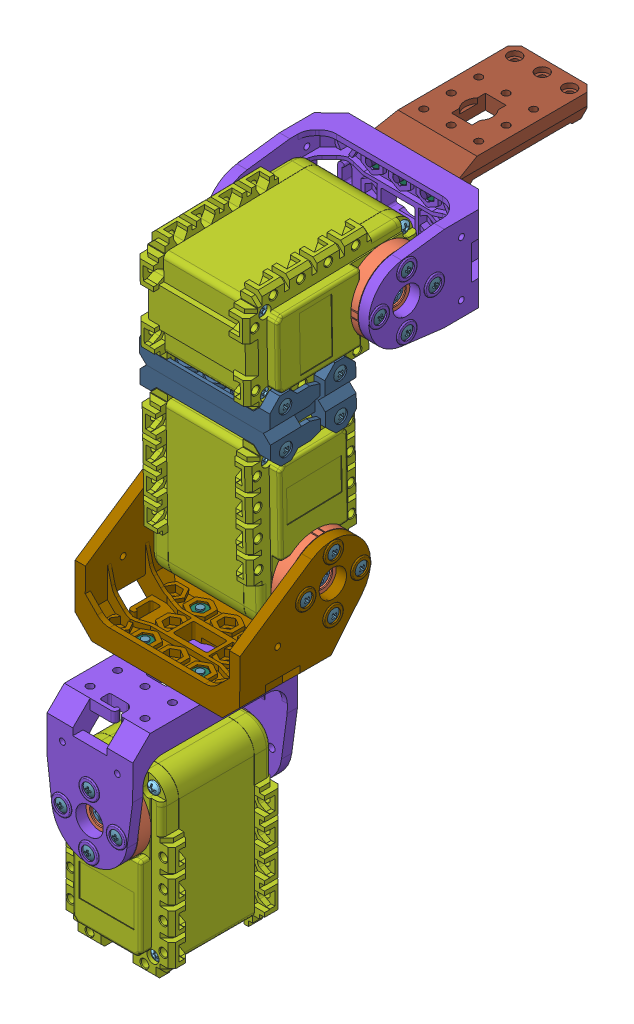
SolidWorks assembly Pate, configuration Défaut. Lengths in mm.
Overall size (51 164.97 135.04).
101 component instances, 17 part files, 139 mates.
Components (placement in the parent):
- AX-12A-1: AX-12A [Défaut] at (-17.6029 32.8619 -0.956) size (32 50.04 40.25)
  - BHS_M2_6X8-1: BHS_M2_6X8 [Défaut] at (0 0 19.48) x (-1 0 0) z (0 1 0) size (5.5 9.6 5.5)
  - DC04_B01_HORN2_DUMMY-1: DC04_B01_HORN2_DUMMY [Défaut] at (0 0 19.03) x (0 1 0) z (0 0 1) size (22 22 6.7)
  - DC04_B01_INSERT_M3-1: DC04_B01_INSERT_M3 [Défaut] at (0 0 -18.4) x (-1 0 0) z (0 1 0) size (4.98 7 4.98)
  - 099990987____-1: 099990987____ [Défaut] at (5.05 -15.19 -9.75) x (1 0 0) z (0 1 0) size (9.9 9.43 4.9)
  - 099990987____-2: 099990987____ [Défaut] at (-4.95 -15.19 -9.75) x (1 0 0) z (0 1 0) size (9.9 9.43 4.9)
  - DX124_SCREW-COVER___-1: DX124_SCREW-COVER___ [Défaut] at (9.5 8.5 14.5) x (-1 0 0) z (0 1 0) size (3.5 30.7 3.5)
  - DX124_SCREW-COVER___-2: DX124_SCREW-COVER___ [Défaut] at (-9.5 8.5 14.5) x (-1 0 0) z (0 1 0) size (3.5 30.7 3.5)
  - DX124_SCREW-COVER___-3: DX124_SCREW-COVER___ [Défaut] at (10.5 -33 14.5) x (-1 0 0) z (0 1 0) size (3.5 30.7 3.5)
  - DX124_SCREW-COVER___-4: DX124_SCREW-COVER___ [Défaut] at (-10.5 -33 14.5) x (-1 0 0) z (0 1 0) size (3.5 30.7 3.5)
  - ASSY_GEAR-WHEEL___DUMMY-1: ASSY_GEAR-WHEEL___DUMMY [Défaut] at (0 0 -2) x (-1 0 0) z (0 0 1) size (6.5 6.5 5.51)
  - ASSY_DUMMY___-1: ASSY_DUMMY___ [Défaut] at origin size (32 50.04 38.37)
- F2-1: F2 [Défaut] at (-17.6029 32.8619 -0.956) x (0 0 -1) z (0.007281 0.999973 0) size (48.81 25 37)
- F1-1: F1 [Défaut] at (-17.2461 81.8606 -23.456) x (0.999973 -0.007281 0) z (-0.007281 -0.999973 0) size (48.81 38 34)
- AX-12A-2: AX-12A [Défaut] at (-17.2461 81.8606 -23.456) x (-0.000183 -0.025088 0.999685) z (0.999973 -0.007281 0) size (32 50.04 40.25)
  - BHS_M2_6X8-1: BHS_M2_6X8 [Défaut] at (0 0 19.48) x (-1 0 0) z (0 1 0) size (5.5 9.6 5.5)
  - DC04_B01_HORN2_DUMMY-1: DC04_B01_HORN2_DUMMY [Défaut] at (0 0 19.03) x (0 1 0) z (0 0 1) size (22 22 6.7)
  - DC04_B01_INSERT_M3-1: DC04_B01_INSERT_M3 [Défaut] at (0 0 -18.4) x (-1 0 0) z (0 1 0) size (4.98 7 4.98)
  - 099990987____-1: 099990987____ [Défaut] at (5.05 -15.19 -9.75) x (1 0 0) z (0 1 0) size (9.9 9.43 4.9)
  - 099990987____-2: 099990987____ [Défaut] at (-4.95 -15.19 -9.75) x (1 0 0) z (0 1 0) size (9.9 9.43 4.9)
  - DX124_SCREW-COVER___-1: DX124_SCREW-COVER___ [Défaut] at (9.5 8.5 14.5) x (-1 0 0) z (0 1 0) size (3.5 30.7 3.5)
  - DX124_SCREW-COVER___-2: DX124_SCREW-COVER___ [Défaut] at (-9.5 8.5 14.5) x (-1 0 0) z (0 1 0) size (3.5 30.7 3.5)
  - DX124_SCREW-COVER___-3: DX124_SCREW-COVER___ [Défaut] at (10.5 -33 14.5) x (-1 0 0) z (0 1 0) size (3.5 30.7 3.5)
  - DX124_SCREW-COVER___-4: DX124_SCREW-COVER___ [Défaut] at (-10.5 -33 14.5) x (-1 0 0) z (0 1 0) size (3.5 30.7 3.5)
  - ASSY_GEAR-WHEEL___DUMMY-1: ASSY_GEAR-WHEEL___DUMMY [Défaut] at (0 0 -2) x (-1 0 0) z (0 0 1) size (6.5 6.5 5.51)
  - ASSY_DUMMY___-1: ASSY_DUMMY___ [Défaut] at origin size (32 50.04 38.37)
- F2-2: F2 [Défaut] at (-16.8017 142.9044 -44.4311) x (0.999973 -0.007281 0) z (0.000029 0.003954 -0.999992) size (48.81 25 37)
- AX-12A-3: AX-12A [Défaut] at (-16.8017 142.9044 -44.4311) x (-0.007279 -0.999659 -0.025089) z (0.999973 -0.007281 0) size (32 50.04 40.25)
  - BHS_M2_6X8-1: BHS_M2_6X8 [Défaut] at (0 0 19.48) x (-1 0 0) z (0 1 0) size (5.5 9.6 5.5)
  - DC04_B01_HORN2_DUMMY-1: DC04_B01_HORN2_DUMMY [Défaut] at (0 0 19.03) x (0 1 0) z (0 0 1) size (22 22 6.7)
  - DC04_B01_INSERT_M3-1: DC04_B01_INSERT_M3 [Défaut] at (0 0 -18.4) x (-1 0 0) z (0 1 0) size (4.98 7 4.98)
  - 099990987____-1: 099990987____ [Défaut] at (5.05 -15.19 -9.75) x (1 0 0) z (0 1 0) size (9.9 9.43 4.9)
  - 099990987____-2: 099990987____ [Défaut] at (-4.95 -15.19 -9.75) x (1 0 0) z (0 1 0) size (9.9 9.43 4.9)
  - DX124_SCREW-COVER___-1: DX124_SCREW-COVER___ [Défaut] at (9.5 8.5 14.5) x (-1 0 0) z (0 1 0) size (3.5 30.7 3.5)
  - DX124_SCREW-COVER___-2: DX124_SCREW-COVER___ [Défaut] at (-9.5 8.5 14.5) x (-1 0 0) z (0 1 0) size (3.5 30.7 3.5)
  - DX124_SCREW-COVER___-3: DX124_SCREW-COVER___ [Défaut] at (10.5 -33 14.5) x (-1 0 0) z (0 1 0) size (3.5 30.7 3.5)
  - DX124_SCREW-COVER___-4: DX124_SCREW-COVER___ [Défaut] at (-10.5 -33 14.5) x (-1 0 0) z (0 1 0) size (3.5 30.7 3.5)
  - ASSY_GEAR-WHEEL___DUMMY-1: ASSY_GEAR-WHEEL___DUMMY [Défaut] at (0 0 -2) x (-1 0 0) z (0 0 1) size (6.5 6.5 5.51)
  - ASSY_DUMMY___-1: ASSY_DUMMY___ [Défaut] at origin size (32 50.04 38.37)
- F3-1: F3 [Défaut] at (-16.9441 123.3464 -22.4149) x (0.000183 0.025088 -0.999685) z (-0.999973 0.007281 0) size (25 9 38)
- F3-2: F3 [Défaut] at (-16.9441 123.3464 -22.4149) x (0.000183 0.025088 -0.999685) z (0.999973 -0.007281 0) size (25 9 38)
- F6-1: F6 [Défaut] at (-16.7025 156.5186 -73.3775) x (-0.000029 -0.003954 0.999992) z (0.999973 -0.007281 0) size (41 9 25)
- BU-1: BU [Défaut] at (-35.6457 81.9946 -23.456) x (0.007281 0.999973 0) z (0 0 1) size (10 7.1 10)
- WA-1: WA [Défaut] at (-36.3456 81.9997 -23.456) x (0.007281 0.999973 0) z (0 0 1) size (12 1.9 12)
- BU-2: BU [Défaut] at (-17.6029 32.8619 -19.356) x (0.963456 -0.267866 0) z (0.267866 0.963456 0) size (10 7.1 10)
- BU-3: BU [Défaut] at (-35.2012 143.0384 -44.4311) x (0.007281 0.999973 0) z (0 0 1) size (10 7.1 10)
- WA-2: WA [Défaut] at (-17.6029 32.8619 -20.056) x (1 0 0) z (0 1 0) size (12 1.9 12)
- WA-3: WA [Défaut] at (-35.9011 143.0435 -44.4311) x (0.007281 0.999973 0) z (0 0 1) size (12 1.9 12)
- S1-1: S1 [B18.6.7M - M2 x 0.4 x 6 Type I Cross Recessed PHMS --6C] at (-17.6612 24.8621 23.644) x (0 0 -1) z (1 0 0) size (7.58 4 4)
- N1-1: N1 [Défaut] at (-25.3872 62.5194 -16.956) x (0.899606 -0.006551 0.436652) z (0.007281 0.999973 0) size (4 4.62 1.6)
- S-B-1: S-B [S-B] at (-17.6029 32.8619 -26.856) x (0 0 1) z (-1 0 0) size (12.37 5.6 5.6)
- S1-2: S1 [B18.6.7M - M2 x 0.4 x 6 Type I Cross Recessed PHMS --6C] at (-17.5447 40.8617 23.644) x (0 0 -1) z (1 0 0) size (7.58 4 4)
- S1-3: S1 [B18.6.7M - M2 x 0.4 x 6 Type I Cross Recessed PHMS --6C] at (-25.6027 32.9201 23.644) x (0 0 -1) z (1 0 0) size (7.58 4 4)
- S1-4: S1 [B18.6.7M - M2 x 0.4 x 6 Type I Cross Recessed PHMS --6C] at (-9.6031 32.8036 23.644) x (0 0 -1) z (1 0 0) size (7.58 4 4)
- N1-2: N1 [Défaut] at (-25.3872 62.5194 -0.956) x (0.934779 -0.006807 0.355164) z (0.007281 0.999973 0) size (4 4.62 1.6)
- N1-3: N1 [Défaut] at (-9.3876 62.4029 -16.956) x (0.962557 -0.007009 0.27099) z (0.007281 0.999973 0) size (4 4.62 1.6)
- N1-4: N1 [Défaut] at (-9.3876 62.4029 -0.956) x (0.901459 -0.006564 0.432814) z (0.007281 0.999973 0) size (4 4.62 1.6)
- S1-5: S1 [B18.6.7M - M2 x 0.4 x 6 Type I Cross Recessed PHMS --6C] at (-9.44 55.2031 -16.956) x (0.007281 0.999973 0) z (0.961495 -0.007001 0.274732) size (7.58 4 4)
- S1-6: S1 [B18.6.7M - M2 x 0.4 x 6 Type I Cross Recessed PHMS --6C] at (-25.4396 55.3196 -0.956) x (0.007281 0.999973 0) z (0.961495 -0.007001 0.274732) size (7.58 4 4)
- S1-7: S1 [B18.6.7M - M2 x 0.4 x 6 Type I Cross Recessed PHMS --6C] at (-25.4396 55.3196 -16.956) x (0.007281 0.999973 0) z (0.961495 -0.007001 0.274732) size (7.58 4 4)
- S1-8: S1 [B18.6.7M - M2 x 0.4 x 6 Type I Cross Recessed PHMS --6C] at (-9.44 55.2031 -0.956) x (0.007281 0.999973 0) z (0.961495 -0.007001 0.274732) size (7.58 4 4)
- S-B-2: S-B [S-B] at (-43.1455 82.0492 -23.456) x (0.999973 -0.007281 0) z (-0.005145 -0.706555 0.707639) size (12.37 5.6 5.6)
- S1-9: S1 [B18.6.7M - M2 x 0.4 x 6 Type I Cross Recessed PHMS --6C] at (7.3532 81.6815 -15.456) x (-0.999973 0.007281 0) z (0.004513 0.619766 -0.784774) size (7.58 4 4)
- S1-10: S1 [B18.6.7M - M2 x 0.4 x 6 Type I Cross Recessed PHMS --6C] at (7.2949 73.6817 -23.456) x (-0.999973 0.007281 0) z (0.004513 0.619766 -0.784774) size (7.58 4 4)
- S1-11: S1 [B18.6.7M - M2 x 0.4 x 6 Type I Cross Recessed PHMS --6C] at (7.3532 81.6815 -31.456) x (-0.999973 0.007281 0) z (0.004513 0.619766 -0.784774) size (7.58 4 4)
- S1-12: S1 [B18.6.7M - M2 x 0.4 x 6 Type I Cross Recessed PHMS --6C] at (7.4115 89.6813 -23.456) x (-0.999973 0.007281 0) z (0.004513 0.619766 -0.784774) size (7.58 4 4)
- S1-13: S1 [B18.6.7M - M2 x 0.4 x 6 Type I Cross Recessed PHMS --6C] at (-24.9686 120.0066 -30.5027) x (0.007279 0.999659 0.025089) z (0.999824 -0.006842 -0.017464) size (7.58 4 4)
- S1-14: S1 [B18.6.7M - M2 x 0.4 x 6 Type I Cross Recessed PHMS --6C] at (-8.969 119.8901 -30.5027) x (0.007279 0.999659 0.025089) z (0.999824 -0.006842 -0.017464) size (7.58 4 4)
- S1-15: S1 [B18.6.7M - M2 x 0.4 x 6 Type I Cross Recessed PHMS --6C] at (-8.9719 119.4887 -14.5077) x (0.007279 0.999659 0.025089) z (0.999824 -0.006842 -0.017464) size (7.58 4 4)
- S1-16: S1 [B18.6.7M - M2 x 0.4 x 6 Type I Cross Recessed PHMS --6C] at (-24.9715 119.6052 -14.5077) x (0.007279 0.999659 0.025089) z (0.615354 0.015298 -0.788102) size (7.58 4 4)
- N1-5: N1 [Défaut] at (-24.9162 127.2042 -30.322) x (0.994741 -0.009802 0.101955) z (0.007279 0.999659 0.025089) size (4 4.62 1.6)
- N1-6: N1 [Défaut] at (-8.9166 127.0877 -30.322) x (0.994741 -0.009802 0.101955) z (0.007279 0.999659 0.025089) size (4 4.62 1.6)
- N1-7: N1 [Défaut] at (-24.9191 126.8028 -14.3271) x (0.994741 -0.009802 0.101955) z (0.007279 0.999659 0.025089) size (4 4.62 1.6)
- N1-8: N1 [Défaut] at (-8.9195 126.6863 -14.3271) x (0.994741 -0.009802 0.101955) z (0.007279 0.999659 0.025089) size (4 4.62 1.6)
- N1-9: N1 [Défaut] at (-2.9059 128.5419 -14.2794) x (-0.003162 -0.434288 0.900768) z (0.999973 -0.007281 0) size (4 4.62 1.6)
- N1-10: N1 [Défaut] at (-2.9859 117.5457 -14.5554) x (-0.003213 -0.441318 0.897345) z (0.999973 -0.007281 0) size (4 4.62 1.6)
- N1-11: N1 [Défaut] at (-29.3823 118.1393 -30.5503) x (-0.003213 -0.441318 0.897345) z (0.999973 -0.007281 0) size (4 4.62 1.6)
- N1-12: N1 [Défaut] at (-30.9051 128.7458 -14.2794) x (0.007178 0.985756 0.168026) z (-0.999973 0.007281 0) size (4 4.62 1.6)
- N1-13: N1 [Défaut] at (-2.9029 128.9433 -30.2744) x (-0.003095 -0.425107 0.905138) z (0.999973 -0.007281 0) size (4 4.62 1.6)
- N1-14: N1 [Défaut] at (-29.3852 117.7379 -14.5554) x (-0.003213 -0.441318 0.897345) z (0.999973 -0.007281 0) size (4 4.62 1.6)
- N1-15: N1 [Défaut] at (-30.9022 129.1472 -30.2744) x (0.007278 0.999569 -0.028446) z (-0.999973 0.007281 0) size (4 4.62 1.6)
- N1-16: N1 [Défaut] at (-2.983 117.9471 -30.5503) x (-0.003213 -0.441318 0.897345) z (0.999973 -0.007281 0) size (4 4.62 1.6)
- S1-17: S1 [B18.6.7M - M2 x 0.4 x 6 Type I Cross Recessed PHMS --6C] at (2.2139 117.5078 -14.5554) x (-0.999973 0.007281 0) z (0.004513 0.619766 -0.784774) size (7.58 4 4)
- S1-18: S1 [B18.6.7M - M2 x 0.4 x 6 Type I Cross Recessed PHMS --6C] at (2.2969 128.9055 -30.2744) x (-0.999973 0.007281 0) z (0.004513 0.619766 -0.784774) size (7.58 4 4)
- S1-19: S1 [B18.6.7M - M2 x 0.4 x 6 Type I Cross Recessed PHMS --6C] at (-36.1851 117.7874 -14.5554) x (0.999973 -0.007281 0) z (-0.004513 -0.619766 -0.784774) size (7.58 4 4)
- S1-20: S1 [B18.6.7M - M2 x 0.4 x 6 Type I Cross Recessed PHMS --6C] at (2.2169 117.9092 -30.5503) x (-0.999973 0.007281 0) z (0.004513 0.619766 -0.784774) size (7.58 4 4)
- S1-21: S1 [B18.6.7M - M2 x 0.4 x 6 Type I Cross Recessed PHMS --6C] at (-36.1821 118.1888 -30.5503) x (0.999973 -0.007281 0) z (-0.004513 -0.619766 -0.784774) size (7.58 4 4)
- S1-22: S1 [B18.6.7M - M2 x 0.4 x 6 Type I Cross Recessed PHMS --6C] at (2.294 128.5041 -14.2794) x (-0.999973 0.007281 0) z (0.004513 0.619766 -0.784774) size (7.58 4 4)
- S1-23: S1 [B18.6.7M - M2 x 0.4 x 6 Type I Cross Recessed PHMS --6C] at (-36.1021 129.1851 -30.2744) x (0.999973 -0.007281 0) z (-0.004513 -0.619766 -0.784774) size (7.58 4 4)
- S1-24: S1 [B18.6.7M - M2 x 0.4 x 6 Type I Cross Recessed PHMS --6C] at (-36.105 128.7837 -14.2794) x (0.999973 -0.007281 0) z (-0.004513 -0.619766 -0.784774) size (7.58 4 4)
- S-B-3: S-B [S-B] at (-42.701 143.093 -44.4311) x (0.999973 -0.007281 0) z (-0.002 -0.274725 0.961521) size (12.37 5.6 5.6)
- S1-25: S1 [B18.6.7M - M2 x 0.4 x 6 Type I Cross Recessed PHMS --6C] at (7.8559 150.725 -44.3995) x (-0.999973 0.007281 0) z (-0.007268 -0.998092 -0.061318) size (7.58 4 4)
- S1-26: S1 [B18.6.7M - M2 x 0.4 x 6 Type I Cross Recessed PHMS --6C] at (7.7979 142.7569 -52.431) x (-0.999973 0.007281 0) z (0.006975 0.957938 0.28689) size (7.58 4 4)
- S1-27: S1 [B18.6.7M - M2 x 0.4 x 6 Type I Cross Recessed PHMS --6C] at (7.7394 134.7256 -44.4627) x (-0.999973 0.007281 0) z (0.003471 0.476707 -0.879056) size (7.58 4 4)
- S1-28: S1 [B18.6.7M - M2 x 0.4 x 6 Type I Cross Recessed PHMS --6C] at (7.7975 142.6937 -36.4312) x (-0.999973 0.007281 0) z (0.00302 0.414752 0.90993) size (7.58 4 4)
- S2-1: S2 [B18.6.7M - M2 x 0.4 x 8 Type I Cross Recessed PHMS --8C] at (-8.7427 150.9669 -74.9992) x (-0.000029 -0.003954 0.999992) z (-0.97462 -0.223862 -0.000913) size (9.58 4 4)
- S2-2: S2 [B18.6.7M - M2 x 0.4 x 8 Type I Cross Recessed PHMS --8C] at (-16.7425 151.0251 -74.9992) x (-0.000029 -0.003954 0.999992) z (-0.766186 -0.642614 -0.002563) size (9.58 4 4)
- S2-3: S2 [B18.6.7M - M2 x 0.4 x 8 Type I Cross Recessed PHMS --8C] at (-24.7423 151.0834 -74.9992) x (-0.000029 -0.003954 0.999992) z (-0.97462 -0.223862 -0.000913) size (9.58 4 4)
- N1-17: N1 [Défaut] at (-8.743 150.9345 -66.7993) x (0.48273 -0.875762 -0.003449) z (-0.000029 -0.003954 0.999992) size (4 4.62 1.6)
- N1-18: N1 [Défaut] at (-16.7428 150.9927 -66.7993) x (0.48273 -0.875762 -0.003449) z (-0.000029 -0.003954 0.999992) size (4 4.62 1.6)
- N1-19: N1 [Défaut] at (-24.7425 151.051 -66.7993) x (0.48273 -0.875762 -0.003449) z (-0.000029 -0.003954 0.999992) size (4 4.62 1.6)
Mates (geometry in assembly coordinates):
- Coaxiale1: concentric anti-aligned: cylinder of AX-12A-1/DC04_B01_HORN2_DUMMY-1 through (-17.6029 32.8619 18.074) axis (0 0 1) radius 11; cylinder of F2-1 through (-17.6029 32.8619 -24.956) axis (0 0 -1) radius 4
- Coaxiale2: concentric aligned: cylinder of BU-2 through (-17.6029 32.8619 -19.356) axis (0 0 -1) radius 4; cylinder of F2-1 through (-17.6029 32.8619 -24.956) axis (0 0 -1) radius 4
- Coïncidente2: coincident anti-aligned: plane of F2-1 through (-17.6029 32.8619 -24.956) normal (0 0 -1); plane of BU-2 through (-17.6029 32.8619 -24.956) normal (0 0 1)
- Coïncidente3: coincident anti-aligned: plane of F2-1 through (-17.6029 32.8619 -21.956) normal (0 0 1); plane of WA-2 through (-17.6029 32.8619 -21.956) normal (0 0 -1)
- Coaxiale4: concentric aligned: cylinder of BU-2 through (-17.6029 32.8619 -19.356) axis (0 0 -1) radius 4; cylinder of WA-2 through (-17.6029 32.8619 -20.056) axis (0 0 -1) radius 6
- Coïncidente4: coincident anti-aligned: plane of AX-12A-1/ASSY_DUMMY___-1 through (-17.6029 32.8619 -19.356) normal (0 0 -1); plane of BU-2 through (-17.6029 32.8619 -19.356) normal (0 0 1)
- Coaxiale5: concentric aligned: cylinder of S-B-1 through (-17.6029 32.8619 -52.256) axis (0 0 -1) radius 1.5; cylinder of BU-2 through (-17.6029 32.8619 -26.456) axis (0 0 -1) radius 1.6
- Coïncidente5: coincident anti-aligned: plane of BU-2 through (-17.6029 32.8619 -24.456) normal (0 0 -1); plane of S-B-1 through (-17.6029 34.3619 -24.456) normal (0 0 1)
- Coïncidente6: coincident anti-aligned: plane of F2-1 through (-17.6029 32.8619 22.044) normal (0 0 1); plane of S1-1 through (-17.6612 25.8621 22.044) normal (0 0 -1)
- Coïncidente7: coincident aligned: plane of S1-1 through (-17.6612 25.8621 22.044) normal (0 0 -1); plane of S1-3 through (-25.6027 33.9201 22.044) normal (0 0 -1)
- Coïncidente8: coincident aligned: plane of S1-3 through (-25.6027 33.9201 22.044) normal (0 0 -1); plane of S1-2 through (-17.5447 41.8617 22.044) normal (0 0 -1)
- Coïncidente9: coincident aligned: plane of S1-4 through (-9.6031 33.8036 22.044) normal (0 0 -1); plane of S1-3 through (-25.6027 33.9201 22.044) normal (0 0 -1)
- Coaxiale7: concentric aligned: cylinder of F2-1 through (-17.6612 24.8621 23.044) axis (0 0 1) radius 1.05; cylinder of S1-1 through (-17.6612 24.8621 49.044) axis (0 0 1) radius 1
- Coaxiale8: concentric aligned: cylinder of F2-1 through (-25.6027 32.9201 23.044) axis (0 0 1) radius 1.05; cylinder of S1-3 through (-25.6027 32.9201 49.044) axis (0 0 1) radius 1
- Coaxiale9: concentric aligned: cylinder of F2-1 through (-17.5447 40.8617 23.044) axis (0 0 1) radius 1.9; cylinder of S1-2 through (-17.5447 40.8617 49.044) axis (0 0 1) radius 1
- Coaxiale11: concentric aligned: cylinder of F2-1 through (-9.6031 32.8036 23.044) axis (0 0 1) radius 1.9; cylinder of S1-4 through (-9.6031 32.8036 49.044) axis (0 0 1) radius 1
- Coïncidente10: coincident anti-aligned: plane of F2-1 through (-29.9133 58.9522 23.044) normal (0.007281 0.999973 0); plane of F1-1 through (-41.413 59.036 3.544) normal (-0.007281 -0.999973 0)
- Coïncidente11: coincident aligned: plane of N1-2 through (-26.0381 60.9241 -4.9046) normal (-0.007281 -0.999973 0); plane of N1-4 through (-9.7029 60.8051 -4.9445) normal (-0.007281 -0.999973 0)
- Coïncidente12: coincident aligned: plane of N1-3 through (-10.3857 60.8101 -20.8325) normal (-0.007281 -0.999973 0); plane of N1-4 through (-9.7029 60.8051 -4.9445) normal (-0.007281 -0.999973 0)
- Coïncidente13: coincident aligned: plane of N1-1 through (-25.6855 60.9215 -20.9458) normal (-0.007281 -0.999973 0); plane of N1-2 through (-26.0381 60.9241 -4.9046) normal (-0.007281 -0.999973 0)
- Coïncidente14: coincident anti-aligned: plane of F1-1 through (-41.3984 61.0359 -23.456) normal (0.007281 0.999973 0); plane of N1-2 through (-26.0381 60.9241 -4.9046) normal (-0.007281 -0.999973 0)
- Coaxiale16: concentric anti-aligned: cylinder of F1-1 through (-9.4138 58.803 -0.956) axis (-0.007281 -0.999973 0) radius 1.05; cylinder of N1-4 through (-9.3993 60.8029 -0.956) axis (0.007281 0.999973 0) radius 1
- Coaxiale17: concentric anti-aligned: cylinder of F1-1 through (-25.4134 58.9195 -0.956) axis (-0.007281 -0.999973 0) radius 1.05; cylinder of N1-2 through (-25.3988 60.9194 -0.956) axis (0.007281 0.999973 0) radius 1
- Coaxiale18: concentric anti-aligned: cylinder of F1-1 through (-9.4138 58.803 -16.956) axis (-0.007281 -0.999973 0) radius 1.05; cylinder of N1-3 through (-9.3993 60.8029 -16.956) axis (0.007281 0.999973 0) radius 1
- Coaxiale19: concentric anti-aligned: cylinder of F1-1 through (-25.4134 58.9195 -16.956) axis (-0.007281 -0.999973 0) radius 1.05; cylinder of N1-1 through (-25.3988 60.9194 -16.956) axis (0.007281 0.999973 0) radius 1
- Coïncidente16: coincident aligned: plane of S1-6 through (-25.7027 56.9215 0.0055) normal (0.007281 0.999973 0); plane of S1-8 through (-9.7031 56.805 0.0055) normal (0.007281 0.999973 0)
- Coïncidente17: coincident aligned: plane of S1-7 through (-25.7027 56.9215 -15.9945) normal (0.007281 0.999973 0); plane of S1-8 through (-9.7031 56.805 0.0055) normal (0.007281 0.999973 0)
- Coïncidente18: coincident aligned: plane of S1-5 through (-9.7031 56.805 -15.9945) normal (0.007281 0.999973 0); plane of S1-7 through (-25.7027 56.9215 -15.9945) normal (0.007281 0.999973 0)
- Coïncidente20: coincident anti-aligned: plane of F2-1 through (-17.4282 56.8613 23.044) normal (-0.007281 -0.999973 0); plane of S1-6 through (-25.7027 56.9215 0.0055) normal (0.007281 0.999973 0)
- Coaxiale20: concentric anti-aligned: cylinder of N1-4 through (-9.3993 60.8029 -0.956) axis (0.007281 0.999973 0) radius 1; cylinder of S1-8 through (-9.625 29.8037 -0.956) axis (-0.007281 -0.999973 0) radius 1
- Coaxiale21: concentric anti-aligned: cylinder of N1-2 through (-25.3988 60.9194 -0.956) axis (0.007281 0.999973 0) radius 1; cylinder of S1-6 through (-25.6246 29.9202 -0.956) axis (-0.007281 -0.999973 0) radius 1
- Coaxiale22: concentric anti-aligned: cylinder of N1-3 through (-9.3993 60.8029 -16.956) axis (0.007281 0.999973 0) radius 1; cylinder of S1-5 through (-9.625 29.8037 -16.956) axis (-0.007281 -0.999973 0) radius 1
- Coaxiale23: concentric anti-aligned: cylinder of N1-1 through (-25.3988 60.9194 -16.956) axis (0.007281 0.999973 0) radius 1; cylinder of S1-7 through (-25.6246 29.9202 -16.956) axis (-0.007281 -0.999973 0) radius 1
- Coaxiale24: concentric anti-aligned: cylinder of F2-1 through (-25.4134 58.9195 -8.956) axis (0.007281 0.999973 0) radius 1.05; cylinder of F1-1 through (-25.4134 58.9195 -8.956) axis (-0.007281 -0.999973 0) radius 1.05
- Coaxiale25: concentric anti-aligned: cylinder of F2-1 through (-9.4138 58.803 -8.956) axis (0.007281 0.999973 0) radius 1.05; cylinder of F1-1 through (-9.4138 58.803 -8.956) axis (-0.007281 -0.999973 0) radius 1.05
- Coaxiale26: concentric anti-aligned: cylinder of F1-1 through (6.7532 81.6858 -23.456) axis (0.999973 -0.007281 0) radius 4; cylinder of BU-1 through (-35.6457 81.9946 -23.456) axis (-0.999973 0.007281 0) radius 4
- Coïncidente21: coincident anti-aligned: plane of F1-1 through (-41.2455 82.0354 -23.456) normal (-0.999973 0.007281 0); plane of BU-1 through (-41.2455 82.0354 -23.456) normal (0.999973 -0.007281 0)
- Coaxiale27: concentric aligned: cylinder of BU-1 through (-35.6457 81.9946 -23.456) axis (-0.999973 0.007281 0) radius 4; cylinder of WA-1 through (-36.3456 81.9997 -23.456) axis (-0.999973 0.007281 0) radius 4.025
- Coïncidente22: coincident anti-aligned: plane of F1-1 through (-38.2456 82.0135 -23.456) normal (0.999973 -0.007281 0); plane of WA-1 through (-38.2456 82.0135 -23.456) normal (-0.999973 0.007281 0)
- Coaxiale28: concentric aligned: cylinder of BU-1 through (-42.7455 82.0463 -23.456) axis (-0.999973 0.007281 0) radius 2.9; cylinder of AX-12A-2/ASSY_DUMMY___-1 through (-33.2457 81.9771 -23.456) axis (-0.999973 0.007281 0) radius 5.5
- Coïncidente23: coincident anti-aligned: plane of AX-12A-2/ASSY_DUMMY___-1 through (-35.6457 81.9946 -23.456) normal (-0.999973 0.007281 0); plane of BU-1 through (-35.6457 81.9946 -23.456) normal (0.999973 -0.007281 0)
- Coïncidente24: coincident anti-aligned: plane of BU-1 through (-40.7455 82.0317 -23.456) normal (-0.999973 0.007281 0); plane of S-B-2 through (-40.7378 83.0931 -22.3962) normal (0.999973 -0.007281 0)
- Coaxiale30: concentric aligned: cylinder of BU-1 through (-42.7455 82.0463 -23.456) axis (-0.999973 0.007281 0) radius 1.6; cylinder of S-B-2 through (-68.5448 82.2341 -23.456) axis (-0.999973 0.007281 0) radius 1.5
- Coïncidente25: coincident aligned: plane of S1-9 through (5.759 82.4779 -14.8363) normal (-0.999973 0.007281 0); plane of S1-11 through (5.759 82.4779 -30.8363) normal (-0.999973 0.007281 0)
- Coïncidente26: coincident aligned: plane of S1-9 through (5.759 82.4779 -14.8363) normal (-0.999973 0.007281 0); plane of S1-10 through (5.7007 74.4781 -22.8363) normal (-0.999973 0.007281 0)
- Coïncidente27: coincident aligned: plane of S1-10 through (5.7007 74.4781 -22.8363) normal (-0.999973 0.007281 0); plane of S1-12 through (5.8172 90.4777 -22.8363) normal (-0.999973 0.007281 0)
- Coïncidente28: coincident anti-aligned: plane of F1-1 through (5.7532 81.6931 -23.456) normal (0.999973 -0.007281 0); plane of S1-9 through (5.759 82.4779 -14.8363) normal (-0.999973 0.007281 0)
- Coaxiale32: concentric anti-aligned: cylinder of F1-1 through (-41.2455 82.0354 -15.456) axis (-0.999973 0.007281 0) radius 1.05; cylinder of S1-9 through (32.7525 81.4965 -15.456) axis (0.999973 -0.007281 0) radius 1
- Coaxiale33: concentric anti-aligned: cylinder of F1-1 through (-41.3038 74.0356 -23.456) axis (-0.999973 0.007281 0) radius 1.05; cylinder of S1-10 through (32.6943 73.4967 -23.456) axis (0.999973 -0.007281 0) radius 1
- Coaxiale34: concentric anti-aligned: cylinder of F1-1 through (-41.2455 82.0354 -31.456) axis (-0.999973 0.007281 0) radius 1.05; cylinder of S1-11 through (32.7525 81.4965 -31.456) axis (0.999973 -0.007281 0) radius 1
- Coaxiale35: concentric anti-aligned: cylinder of F1-1 through (-41.1873 90.0351 -23.456) axis (-0.999973 0.007281 0) radius 1.05; cylinder of S1-12 through (32.8108 89.4963 -23.456) axis (0.999973 -0.007281 0) radius 1
- Coïncidente29: coincident anti-aligned: plane of F3-1 through (-16.9441 123.3464 -22.4149) normal (0.007279 0.999659 0.025089); plane of F3-2 through (-16.9441 123.3464 -22.4149) normal (-0.007279 -0.999659 -0.025089)
- Coaxiale36: concentric anti-aligned: cylinder of F3-1 through (-8.9457 123.0875 -14.4174) axis (0.007279 0.999659 0.025089) radius 1.05; cylinder of F3-2 through (-8.9457 123.0875 -14.4174) axis (-0.007279 -0.999659 -0.025089) radius 1.05
- Coaxiale37: concentric anti-aligned: cylinder of F3-1 through (-24.9453 123.204 -14.4174) axis (0.007279 0.999659 0.025089) radius 1.05; cylinder of F3-2 through (-24.9453 123.204 -14.4174) axis (-0.007279 -0.999659 -0.025089) radius 1.05
- Coïncidente30: coincident anti-aligned: plane of AX-12A-2/ASSY_DUMMY___-1 through (-1.2466 81.7441 -23.456) normal (0.999973 -0.007281 0); plane of F3-1 through (-0.9686 119.9174 -9.9941) normal (-0.999973 0.007281 0)
- Coïncidente33: coincident aligned: plane of S1-14 through (-8.9401 121.4644 -29.463) normal (0.007279 0.999659 0.025089); plane of S1-15 through (-8.943 121.063 -13.468) normal (0.007279 0.999659 0.025089)
- Coïncidente36: coincident aligned: plane of S1-15 through (-8.943 121.063 -13.468) normal (0.007279 0.999659 0.025089); plane of S1-16 through (-24.1717 121.1835 -13.8525) normal (0.007279 0.999659 0.025089)
- Coïncidente37: coincident aligned: plane of S1-13 through (-24.9397 121.5809 -29.463) normal (0.007279 0.999659 0.025089); plane of S1-14 through (-8.9401 121.4644 -29.463) normal (0.007279 0.999659 0.025089)
- Coaxiale38: concentric anti-aligned: cylinder of F3-1 through (-24.9424 123.6054 -30.4123) axis (0.007279 0.999659 0.025089) radius 1.05; cylinder of S1-13 through (-25.1535 94.6153 -31.1399) axis (-0.007279 -0.999659 -0.025089) radius 1
- Coaxiale39: concentric anti-aligned: cylinder of F3-1 through (-24.9453 123.204 -14.4174) axis (0.007279 0.999659 0.025089) radius 1.05; cylinder of S1-16 through (-25.1564 94.2139 -15.145) axis (-0.007279 -0.999659 -0.025089) radius 1
- Coaxiale40: concentric anti-aligned: cylinder of F3-1 through (-8.9457 123.0875 -14.4174) axis (0.007279 0.999659 0.025089) radius 1.05; cylinder of S1-15 through (-9.1568 94.0974 -15.145) axis (-0.007279 -0.999659 -0.025089) radius 1
- Coaxiale41: concentric anti-aligned: cylinder of F3-1 through (-8.9428 123.4889 -30.4123) axis (0.007279 0.999659 0.025089) radius 1.05; cylinder of S1-14 through (-9.1539 94.4988 -31.1399) axis (-0.007279 -0.999659 -0.025089) radius 1
- Coïncidente38: coincident anti-aligned: plane of F3-1 through (-16.9586 121.3471 -22.465) normal (-0.007279 -0.999659 -0.025089); plane of S1-15 through (-8.943 121.063 -13.468) normal (0.007279 0.999659 0.025089)
- Coïncidente39: coincident aligned: plane of N1-6 through (-10.5522 127.1911 -33.9709) normal (0.007279 0.999659 0.025089); plane of N1-8 through (-10.5551 126.7897 -17.9759) normal (0.007279 0.999659 0.025089)
- Coïncidente40: coincident aligned: plane of N1-6 through (-10.5522 127.1911 -33.9709) normal (0.007279 0.999659 0.025089); plane of N1-7 through (-26.5547 126.9062 -17.9759) normal (0.007279 0.999659 0.025089)
- Coïncidente41: coincident aligned: plane of N1-5 through (-26.5518 127.3076 -33.9709) normal (0.007279 0.999659 0.025089); plane of N1-6 through (-10.5522 127.1911 -33.9709) normal (0.007279 0.999659 0.025089)
- Coïncidente42: coincident anti-aligned: plane of F3-2 through (-16.9295 125.3458 -22.3647) normal (0.007279 0.999659 0.025089); plane of N1-5 through (-26.5634 125.7082 -34.011) normal (-0.007279 -0.999659 -0.025089)
- Coaxiale42: concentric anti-aligned: cylinder of S1-13 through (-25.1535 94.6153 -31.1399) axis (-0.007279 -0.999659 -0.025089) radius 1; cylinder of N1-5 through (-24.9278 125.6047 -30.3622) axis (0.007279 0.999659 0.025089) radius 1
- Coaxiale43: concentric anti-aligned: cylinder of S1-16 through (-25.1564 94.2139 -15.145) axis (-0.007279 -0.999659 -0.025089) radius 1; cylinder of N1-7 through (-24.9308 125.2033 -14.3672) axis (0.007279 0.999659 0.025089) radius 1
- Coaxiale44: concentric anti-aligned: cylinder of S1-14 through (-9.1539 94.4988 -31.1399) axis (-0.007279 -0.999659 -0.025089) radius 1; cylinder of N1-6 through (-8.9283 125.4882 -30.3622) axis (0.007279 0.999659 0.025089) radius 1
- Coaxiale45: concentric anti-aligned: cylinder of S1-15 through (-9.1568 94.0974 -15.145) axis (-0.007279 -0.999659 -0.025089) radius 1; cylinder of N1-8 through (-8.9312 125.0868 -14.3672) axis (0.007279 0.999659 0.025089) radius 1
- Coaxiale48: concentric anti-aligned: cylinder of F3-2 through (2.094 128.5055 -14.2794) axis (0.999973 -0.007281 0) radius 1.05; cylinder of N1-12 through (-29.3052 128.7341 -14.2794) axis (-0.999973 0.007281 0) radius 1
- Coaxiale49: concentric anti-aligned: cylinder of N1-9 through (-4.5058 128.5536 -14.2794) axis (0.999973 -0.007281 0) radius 1; cylinder of N1-12 through (-29.3052 128.7341 -14.2794) axis (-0.999973 0.007281 0) radius 1
- Coaxiale50: concentric anti-aligned: cylinder of F3-2 through (2.0969 128.9069 -30.2744) axis (0.999973 -0.007281 0) radius 1.05; cylinder of N1-15 through (-29.3022 129.1356 -30.2744) axis (-0.999973 0.007281 0) radius 1
- Coaxiale51: concentric aligned: cylinder of F3-2 through (2.0969 128.9069 -30.2744) axis (0.999973 -0.007281 0) radius 1.05; cylinder of N1-13 through (-4.5029 128.955 -30.2744) axis (0.999973 -0.007281 0) radius 1
- Coaxiale52: concentric anti-aligned: cylinder of F3-1 through (-35.9851 117.786 -14.5554) axis (-0.999973 0.007281 0) radius 1.05; cylinder of N1-14 through (-30.9852 117.7495 -14.5554) axis (0.999973 -0.007281 0) radius 1
- Coaxiale53: concentric anti-aligned: cylinder of F3-1 through (-35.9851 117.786 -14.5554) axis (-0.999973 0.007281 0) radius 1.05; cylinder of N1-10 through (-4.5859 117.5573 -14.5554) axis (0.999973 -0.007281 0) radius 1
- Coaxiale54: concentric anti-aligned: cylinder of F3-1 through (-35.9821 118.1874 -30.5503) axis (-0.999973 0.007281 0) radius 1.05; cylinder of N1-16 through (-4.583 117.9587 -30.5503) axis (0.999973 -0.007281 0) radius 1
- Coaxiale55: concentric anti-aligned: cylinder of F3-1 through (-35.9821 118.1874 -30.5503) axis (-0.999973 0.007281 0) radius 1.05; cylinder of N1-11 through (-30.9823 118.151 -30.5503) axis (0.999973 -0.007281 0) radius 1
- Distance1: distance = 2 mm anti-aligned: plane of N1-9 through (-2.9223 126.2902 -17.5854) normal (0.999973 -0.007281 0); plane of F3-2 through (-0.9204 126.5425 -34.8357) normal (-0.999973 0.007281 0)
- Coïncidente52: coincident aligned: plane of N1-9 through (-4.5222 126.3019 -17.5854) normal (-0.999973 0.007281 0); plane of N1-13 through (-4.5195 126.6698 -33.5573) normal (-0.999973 0.007281 0)
- Distance2: distance = 2 mm anti-aligned: plane of F3-2 through (-32.9241 126.1483 -9.8435) normal (0.999973 -0.007281 0); plane of N1-12 through (-30.9152 127.3563 -18.0303) normal (-0.999973 0.007281 0)
- Coïncidente54: coincident aligned: plane of N1-12 through (-29.3153 127.3447 -18.0303) normal (0.999973 -0.007281 0); plane of N1-15 through (-29.3175 127.0379 -33.6802) normal (0.999973 -0.007281 0)
- Coïncidente55: coincident aligned: plane of N1-9 through (-4.5222 126.3019 -17.5854) normal (-0.999973 0.007281 0); plane of N1-10 through (-4.6021 115.3315 -17.8789) normal (-0.999973 0.007281 0)
- Coïncidente56: coincident aligned: plane of N1-13 through (-4.5195 126.6698 -33.5573) normal (-0.999973 0.007281 0); plane of N1-16 through (-4.5992 115.733 -33.8738) normal (-0.999973 0.007281 0)
- Coïncidente57: coincident aligned: plane of N1-12 through (-29.3153 127.3447 -18.0303) normal (0.999973 -0.007281 0); plane of N1-14 through (-29.4014 115.5121 -17.8789) normal (0.999973 -0.007281 0)
- Coïncidente58: coincident aligned: plane of N1-11 through (-29.3985 115.9135 -33.8738) normal (0.999973 -0.007281 0); plane of N1-14 through (-29.4014 115.5121 -17.8789) normal (0.999973 -0.007281 0)
- Coaxiale57: concentric anti-aligned: cylinder of AX-12A-2/ASSY_DUMMY___-1 through (-0.986 117.5311 -14.5554) axis (0.999973 -0.007281 0) radius 1.1; cylinder of F3-1 through (-35.9851 117.786 -14.5554) axis (-0.999973 0.007281 0) radius 1.05
- Coaxiale58: concentric aligned: cylinder of AX-12A-2/ASSY_DUMMY___-1 through (-0.9831 117.9325 -30.5503) axis (-0.999973 0.007281 0) radius 1.1; cylinder of F3-1 through (-35.9821 118.1874 -30.5503) axis (-0.999973 0.007281 0) radius 1.05
- Coïncidente59: coincident aligned: plane of S1-17 through (0.6197 118.3042 -13.9356) normal (-0.999973 0.007281 0); plane of S1-20 through (0.6226 118.7056 -29.9305) normal (-0.999973 0.007281 0)
- Coïncidente60: coincident aligned: plane of S1-18 through (0.7027 129.7019 -29.6546) normal (-0.999973 0.007281 0); plane of S1-20 through (0.6226 118.7056 -29.9305) normal (-0.999973 0.007281 0)
- Coïncidente61: coincident aligned: plane of S1-18 through (0.7027 129.7019 -29.6546) normal (-0.999973 0.007281 0); plane of S1-22 through (0.6998 129.3005 -13.6596) normal (-0.999973 0.007281 0)
- Coaxiale59: concentric aligned: cylinder of F3-1 through (2.0139 117.5093 -14.5554) axis (0.999973 -0.007281 0) radius 1.9; cylinder of S1-17 through (27.6133 117.3229 -14.5554) axis (0.999973 -0.007281 0) radius 1
- Coaxiale60: concentric aligned: cylinder of F3-1 through (2.0169 117.9107 -30.5503) axis (0.999973 -0.007281 0) radius 1.9; cylinder of S1-20 through (27.6162 117.7243 -30.5503) axis (0.999973 -0.007281 0) radius 1
- Coaxiale61: concentric aligned: cylinder of F3-2 through (2.0969 128.9069 -30.2744) axis (0.999973 -0.007281 0) radius 1.9; cylinder of S1-18 through (27.6962 128.7205 -30.2744) axis (0.999973 -0.007281 0) radius 1
- Coaxiale62: concentric aligned: cylinder of F3-2 through (2.094 128.5055 -14.2794) axis (0.999973 -0.007281 0) radius 1.05; cylinder of S1-22 through (27.6933 128.3191 -14.2794) axis (0.999973 -0.007281 0) radius 1
- Coïncidente62: coincident anti-aligned: plane of F3-2 through (0.6555 123.2183 -22.4149) normal (0.999973 -0.007281 0); plane of S1-22 through (0.6998 129.3005 -13.6596) normal (-0.999973 0.007281 0)
- Coïncidente63: coincident aligned: plane of S1-21 through (-34.5879 117.3924 -29.9305) normal (0.999973 -0.007281 0); plane of S1-23 through (-34.5078 128.3887 -29.6546) normal (0.999973 -0.007281 0)
- Coïncidente64: coincident aligned: plane of S1-19 through (-34.5908 116.991 -13.9356) normal (0.999973 -0.007281 0); plane of S1-23 through (-34.5078 128.3887 -29.6546) normal (0.999973 -0.007281 0)
- Coïncidente65: coincident aligned: plane of S1-19 through (-34.5908 116.991 -13.9356) normal (0.999973 -0.007281 0); plane of S1-24 through (-34.5107 127.9873 -13.6596) normal (0.999973 -0.007281 0)
- Coïncidente66: coincident anti-aligned: plane of S1-24 through (-34.5107 127.9873 -13.6596) normal (0.999973 -0.007281 0); plane of F3-2 through (-34.5436 123.4746 -22.4149) normal (-0.999973 0.007281 0)
- Coaxiale63: concentric aligned: cylinder of F3-1 through (-35.9851 117.786 -14.5554) axis (-0.999973 0.007281 0) radius 1.9; circle of S1-19
- Coaxiale64: concentric aligned: cylinder of F3-2 through (-35.905 128.7822 -14.2794) axis (-0.999973 0.007281 0) radius 1.9; cylinder of S1-24 through (-61.5043 128.9686 -14.2794) axis (-0.999973 0.007281 0) radius 1
- Coaxiale65: concentric aligned: cylinder of F3-2 through (-35.9021 129.1836 -30.2744) axis (-0.999973 0.007281 0) radius 1.9; cylinder of S1-23 through (-61.5014 129.37 -30.2744) axis (-0.999973 0.007281 0) radius 1
- Coaxiale66: concentric aligned: cylinder of F3-1 through (-35.9821 118.1874 -30.5503) axis (-0.999973 0.007281 0) radius 1.9; cylinder of S1-21 through (-61.5815 118.3738 -30.5503) axis (-0.999973 0.007281 0) radius 1
- Coïncidente67: coincident anti-aligned: plane of AX-12A-3/ASSY_DUMMY___-1 through (-32.8012 143.0209 -44.4311) normal (-0.999973 0.007281 0); plane of F3-2 through (-32.9241 126.1483 -9.8435) normal (0.999973 -0.007281 0)
- Coaxiale67: concentric anti-aligned: circle of AX-12A-3/ASSY_DUMMY___-1; cylinder of S1-22 through (27.6933 128.3191 -14.2794) axis (0.999973 -0.007281 0) radius 1
- Coaxiale68: concentric anti-aligned: cylinder of AX-12A-3/ASSY_DUMMY___-1 through (-32.9021 129.1618 -30.2744) axis (0.999973 -0.007281 0) radius 1.1; cylinder of S1-23 through (-61.5014 129.37 -30.2744) axis (-0.999973 0.007281 0) radius 1
- Coaxiale69: concentric anti-aligned: cylinder of F2-2 through (7.1977 142.7297 -44.4311) axis (0.999973 -0.007281 0) radius 4; cylinder of AX-12A-3/ASSY_DUMMY___-1 through (-32.8012 143.0209 -44.4311) axis (-0.999973 0.007281 0) radius 5.5
- Coaxiale70: concentric anti-aligned: cylinder of F2-2 through (7.1977 142.7297 -44.4311) axis (0.999973 -0.007281 0) radius 4; cylinder of BU-3 through (-35.2012 143.0384 -44.4311) axis (-0.999973 0.007281 0) radius 4
- Coïncidente68: coincident anti-aligned: plane of F2-2 through (-40.801 143.0792 -44.4311) normal (-0.999973 0.007281 0); plane of BU-3 through (-40.801 143.0792 -44.4311) normal (0.999973 -0.007281 0)
- Coïncidente69: coincident anti-aligned: plane of F2-2 through (-37.8011 143.0573 -44.4311) normal (0.999973 -0.007281 0); plane of WA-3 through (-37.8011 143.0573 -44.4311) normal (-0.999973 0.007281 0)
- Coaxiale71: concentric aligned: cylinder of AX-12A-3/ASSY_DUMMY___-1 through (-32.8012 143.0209 -44.4311) axis (-0.999973 0.007281 0) radius 5.5; cylinder of WA-3 through (-35.9011 143.0435 -44.4311) axis (-0.999973 0.007281 0) radius 6
- Coïncidente70: coincident anti-aligned: plane of AX-12A-3/ASSY_DUMMY___-1 through (-35.2012 143.0384 -44.4311) normal (-0.999973 0.007281 0); plane of BU-3 through (-35.2012 143.0384 -44.4311) normal (0.999973 -0.007281 0)
- Coaxiale72: concentric aligned: cylinder of BU-3 through (-42.301 143.0901 -44.4311) axis (-0.999973 0.007281 0) radius 2.9; cylinder of S-B-3 through (-68.1003 143.278 -44.4311) axis (-0.999973 0.007281 0) radius 1.5
- Coïncidente71: coincident anti-aligned: plane of BU-3 through (-40.301 143.0755 -44.4311) normal (-0.999973 0.007281 0); plane of S-B-3 through (-40.2905 144.5178 -44.019) normal (0.999973 -0.007281 0)
- Coaxiale73: concentric anti-aligned: cylinder of F2-2 through (-40.8012 143.0476 -36.4312) axis (-0.999973 0.007281 0) radius 1.05; cylinder of S1-28 through (33.1968 142.5087 -36.4312) axis (0.999973 -0.007281 0) radius 1
- Coaxiale74: concentric anti-aligned: cylinder of F2-2 through (-40.8593 135.0795 -44.4627) axis (-0.999973 0.007281 0) radius 1.05; cylinder of S1-27 through (33.1388 134.5406 -44.4627) axis (0.999973 -0.007281 0) radius 1
- Coaxiale75: concentric anti-aligned: cylinder of F2-2 through (-40.8008 143.1108 -52.431) axis (-0.999973 0.007281 0) radius 1.05; cylinder of S1-26 through (33.1973 142.572 -52.431) axis (0.999973 -0.007281 0) radius 1
- Coaxiale76: concentric anti-aligned: cylinder of F2-2 through (-40.7428 151.0789 -44.3995) axis (-0.999973 0.007281 0) radius 1.05; cylinder of S1-25 through (33.2553 150.5401 -44.3995) axis (0.999973 -0.007281 0) radius 1
- Coïncidente72: coincident anti-aligned: plane of F2-2 through (6.1977 142.737 -44.4311) normal (0.999973 -0.007281 0); plane of S1-25 through (6.2564 150.798 -45.3976) normal (-0.999973 0.007281 0)
- Coïncidente73: coincident anti-aligned: plane of F2-2 through (6.1977 142.737 -44.4311) normal (0.999973 -0.007281 0); plane of S1-26 through (6.1959 142.4817 -51.4731) normal (-0.999973 0.007281 0)
- Coïncidente74: coincident anti-aligned: plane of F2-2 through (6.1977 142.737 -44.4311) normal (0.999973 -0.007281 0); plane of S1-27 through (6.1459 135.6163 -43.986) normal (-0.999973 0.007281 0)
- Coïncidente75: coincident anti-aligned: plane of F2-2 through (6.1977 142.737 -44.4311) normal (0.999973 -0.007281 0); plane of S1-28 through (6.1909 141.7954 -36.0164) normal (-0.999973 0.007281 0)
- Coïncidente76: coincident anti-aligned: plane of F2-2 through (-40.8913 130.6824 -70.4803) normal (0.000029 0.003954 -0.999992); plane of F6-1 through (-16.7026 156.5068 -70.3775) normal (-0.000029 -0.003954 0.999992)
- Coaxiale77: concentric anti-aligned: cylinder of F2-2 through (-8.7429 150.9487 -70.3993) axis (0.000029 0.003954 -0.999992) radius 1.05; cylinder of F6-1 through (-8.7429 150.9487 -70.3993) axis (-0.000029 -0.003954 0.999992) radius 1.05
- Coïncidente77: coincident aligned: cylinder of F2-2 through (-24.7424 151.0652 -70.3993) axis (0.000029 0.003954 -0.999992) radius 1.05; circle of F6-1
- Coaxiale81: concentric aligned: cylinder of F2-2 through (-8.7429 150.9487 -70.3993) axis (0.000029 0.003954 -0.999992) radius 1.05; cylinder of S2-1 through (-8.742 151.0673 -100.399) axis (0.000029 0.003954 -0.999992) radius 1
- Coaxiale82: concentric aligned: cylinder of F2-2 through (-16.7427 151.007 -70.3993) axis (0.000029 0.003954 -0.999992) radius 1.05; cylinder of S2-2 through (-16.7418 151.1256 -100.399) axis (0.000029 0.003954 -0.999992) radius 1
- Coaxiale83: concentric aligned: cylinder of F2-2 through (-24.7424 151.0652 -70.3993) axis (0.000029 0.003954 -0.999992) radius 1.05; cylinder of S2-3 through (-24.7416 151.1838 -100.399) axis (0.000029 0.003954 -0.999992) radius 1
- Coïncidente81: coincident aligned: plane of S2-2 through (-17.3852 151.785 -73.3962) normal (-0.000029 -0.003954 0.999992); plane of S2-3 through (-24.9662 152.0517 -73.3954) normal (-0.000029 -0.003954 0.999992)
- Coïncidente82: coincident anti-aligned: plane of F6-1 through (-16.7025 156.5186 -73.3775) normal (0.000029 0.003954 -0.999992); plane of S2-3 through (-24.9662 152.0517 -73.3954) normal (-0.000029 -0.003954 0.999992)
- Coïncidente83: coincident anti-aligned: plane of F6-1 through (-16.7025 156.5186 -73.3775) normal (0.000029 0.003954 -0.999992); plane of S2-1 through (-8.9666 151.9352 -73.3954) normal (-0.000029 -0.003954 0.999992)
- Coïncidente84: coincident aligned: plane of N1-17 through (-6.6747 154.3582 -66.7857) normal (-0.000029 -0.003954 0.999992); plane of N1-19 through (-22.6743 154.4747 -66.7857) normal (-0.000029 -0.003954 0.999992)
- Coïncidente85: coincident aligned: plane of N1-18 through (-14.6745 154.4165 -66.7857) normal (-0.000029 -0.003954 0.999992); plane of N1-19 through (-22.6743 154.4747 -66.7857) normal (-0.000029 -0.003954 0.999992)
- Coaxiale84: concentric anti-aligned: cylinder of S2-3 through (-24.7416 151.1838 -100.399) axis (0.000029 0.003954 -0.999992) radius 1; cylinder of N1-19 through (-24.7425 151.0573 -68.3993) axis (-0.000029 -0.003954 0.999992) radius 1
- Coïncidente86: coincident anti-aligned: plane of F2-2 through (-40.8003 143.1741 -68.4309) normal (-0.000029 -0.003954 0.999992); plane of N1-19 through (-22.6742 154.481 -68.3857) normal (0.000029 0.003954 -0.999992)
- Coaxiale85: concentric anti-aligned: cylinder of S2-2 through (-16.7418 151.1256 -100.399) axis (0.000029 0.003954 -0.999992) radius 1; cylinder of N1-18 through (-16.7427 150.9991 -68.3993) axis (-0.000029 -0.003954 0.999992) radius 1
- Coaxiale86: concentric anti-aligned: cylinder of S2-1 through (-8.742 151.0673 -100.399) axis (0.000029 0.003954 -0.999992) radius 1; cylinder of N1-17 through (-8.7429 150.9408 -68.3993) axis (-0.000029 -0.003954 0.999992) radius 1
